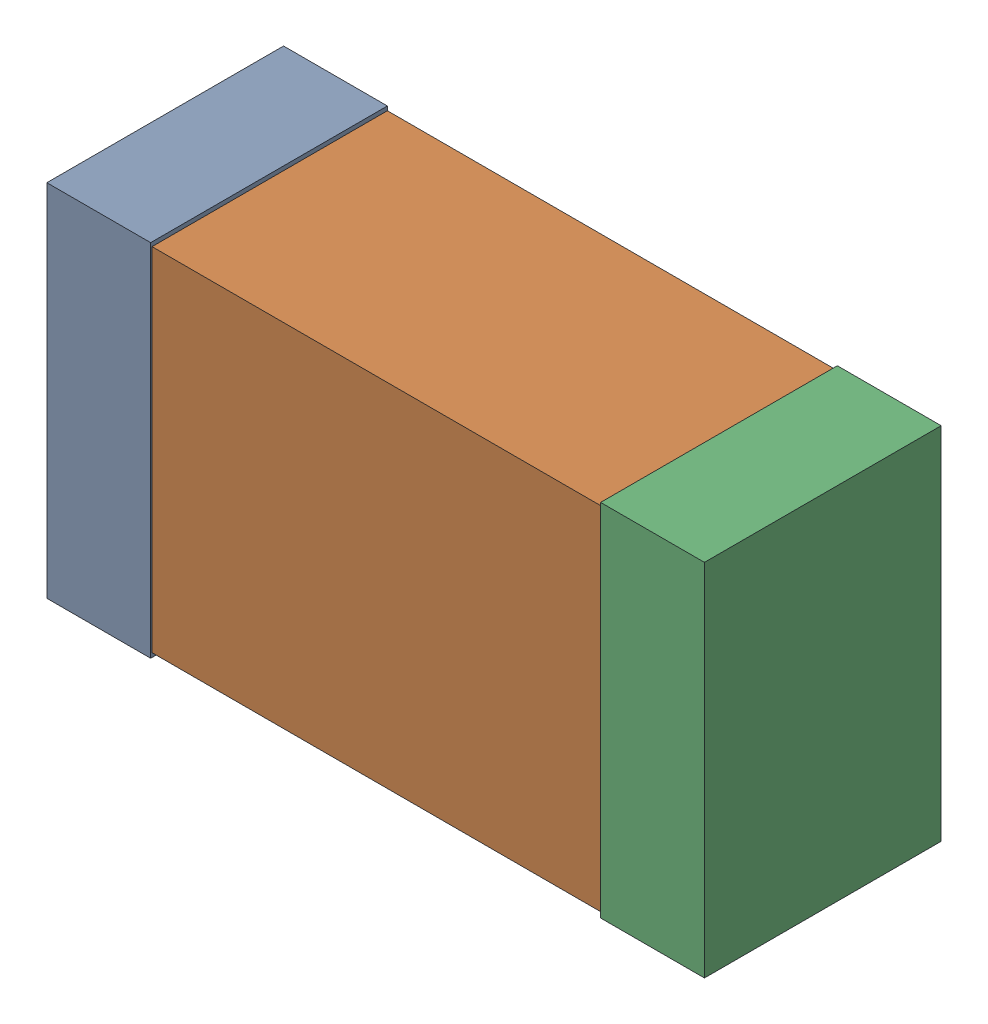
SolidWorks assembly C14_Motor_3Kanaloa_v2.0.0_Motor, configuration Default. Lengths in mm.
Overall size (2.38 1.3 0.85).
6 component instances, 2 part files, 0 mates.
Components (placement in the parent):
- 352877648-1: 352877648 [Default] at (34.263 83.82 0) size (0.38 1.3 0.85)
  - Extruded_14-1: Extruded_14 [Default] at origin size (0.38 1.3 0.85)
- 352877392-1: 352877392 [Default] at (35.263 83.82 0) size (2.2 1.27 0.85)
  - Extruded_15-1: Extruded_15 [Default] at origin size (2.2 1.27 0.85)
- 352877648-2: 352877648 [Default] at (36.263 83.82 0) size (0.38 1.3 0.85)
  - Extruded_14-1: Extruded_14 [Default] at origin size (0.38 1.3 0.85)
